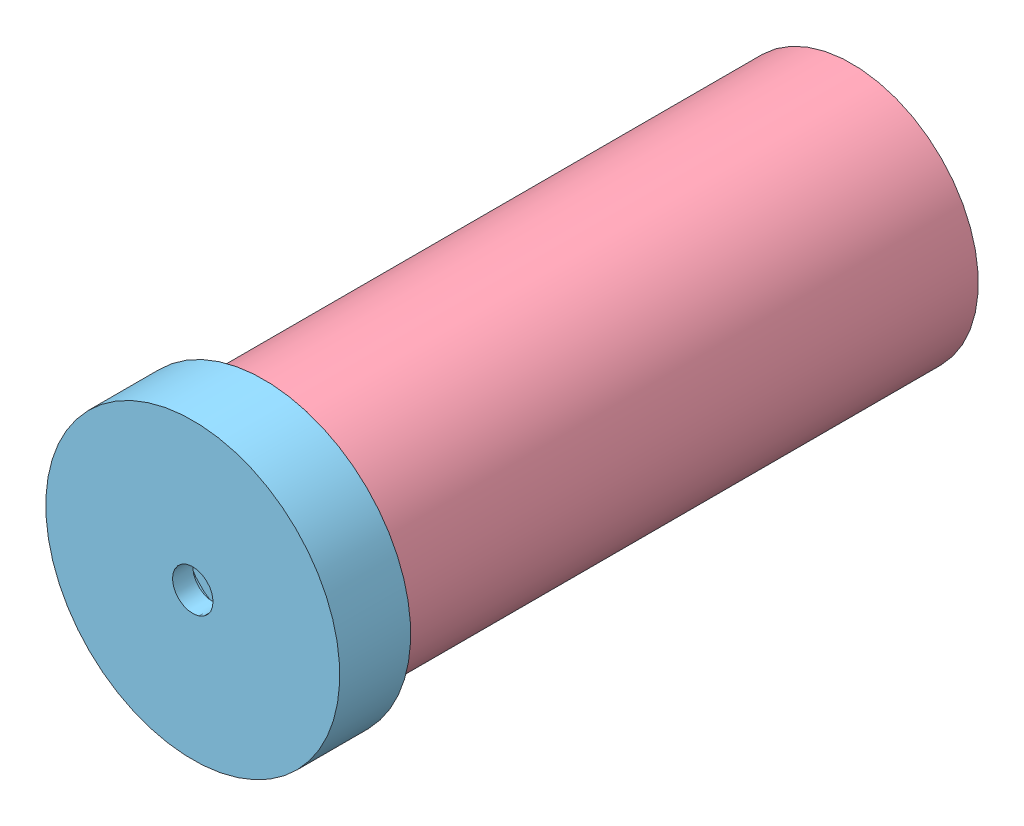
SolidWorks assembly [CC] Combustion Chamber, configuration Default. Lengths in mm.
Overall size (231.49 231.49 456.39).
6 component instances, 5 part files, 12 mates.
Components (placement in the parent):
- [CC] Inner Chamber Wall-1: [CC] Inner Chamber Wall [Default] at origin size (146.05 146.05 254)
- [CC] Inner Nozzle Wall-1: [CC] Inner Nozzle Wall [Default] at (0 0 -313.329) size (152.4 152.4 181.16)
- [CC] Throat Ring-1: [CC] Throat Ring [Default] at (0 0 -313.329) x (0.999908 0.013577 0) z (0 0 1) size (154.53 74.93 94.62)
- [CC] Throat Ring-2: [CC] Throat Ring [Default] at (0 0 -313.329) x (-0.999908 -0.013577 0) z (0 0 1) size (154.53 74.93 94.62)
- [CC] Outer Casing-1: [CC] Outer Casing [Default] x (0.997288 -0.073598 0) z (0 0 1) size (158.75 158.75 387.35)
- [CC] Injector Core-1: [CC] Injector Core [Default] at (0 0 -50.8) x (-0.952485 -0.304584 0) z (0 0 -1) size (184.15 184.15 76.2)
Mates (geometry in assembly coordinates):
- Concentric1: concentric aligned: cylinder of [CC] Inner Chamber Wall-1 through (0 0 -254) axis (0 0 1) radius 66.675; cylinder of [CC] Inner Nozzle Wall-1 through (0 0 -313.329) axis (0 0 1) radius 66.675
- Coincident1: coincident aligned: plane of [CC] Inner Chamber Wall-1 through (0 0 0) normal (1 0 0); plane of [CC] Inner Nozzle Wall-1 through (0 0 -313.329) normal (1 0 0)
- Coincident2: coincident aligned: plane of [CC] Inner Nozzle Wall-1 through (0 0 -313.329) normal (0 0 1); plane of [CC] Throat Ring-1 through (0 0 -313.329) normal (0 0 1)
- Concentric3: concentric anti-aligned: cylinder of [CC] Throat Ring-1 through (0 0 -313.329) axis (0 0 -1) radius 76.2
- Concentric4: concentric anti-aligned: cylinder of [CC] Throat Ring-2 through (0 0 -313.329) axis (0 0 -1) radius 76.2
- Parallel1: parallel anti-aligned: plane of [CC] Throat Ring-1 through (-0.0172 1.2699 -313.329) normal (0.013577 -0.999908 0); plane of [CC] Throat Ring-2 through (0.0172 -1.2699 -313.329) normal (-0.013577 0.999908 0)
- Coincident3: coincident aligned: plane of [CC] Throat Ring-1 through (0 0 -313.329) normal (0 0 1); plane of [CC] Throat Ring-2 through (0 0 -313.329) normal (0 0 1)
- Concentric5: concentric aligned: cylinder of [CC] Outer Casing-1 through (0 0 -387.35) axis (0 0 1) radius 79.375
- Coincident4: coincident aligned: plane of [CC] Inner Chamber Wall-1 through (0 0 0) normal (0 0 1); plane of [CC] Outer Casing-1 through (0 0 0) normal (0 0 1)
- Coincident5: coincident aligned: plane of [CC] Inner Nozzle Wall-1 through (0 0 -387.35) normal (0 0 -1); plane of [CC] Outer Casing-1 through (0 0 -387.35) normal (0 0 -1)
- Concentric7: concentric: cylinder of assembly; cylinder of [CC] Injector Core-1 through (-1.1539 8.0567 44.45) axis (0 0 1) radius 92.075; line of assembly
- Coincident9: coincident anti-aligned: plane of [CC] Inner Chamber Wall-1 through (0 0 0) normal (0 0 1); plane of [CC] Injector Core-1 through (0 0 0) normal (0 0 -1)
